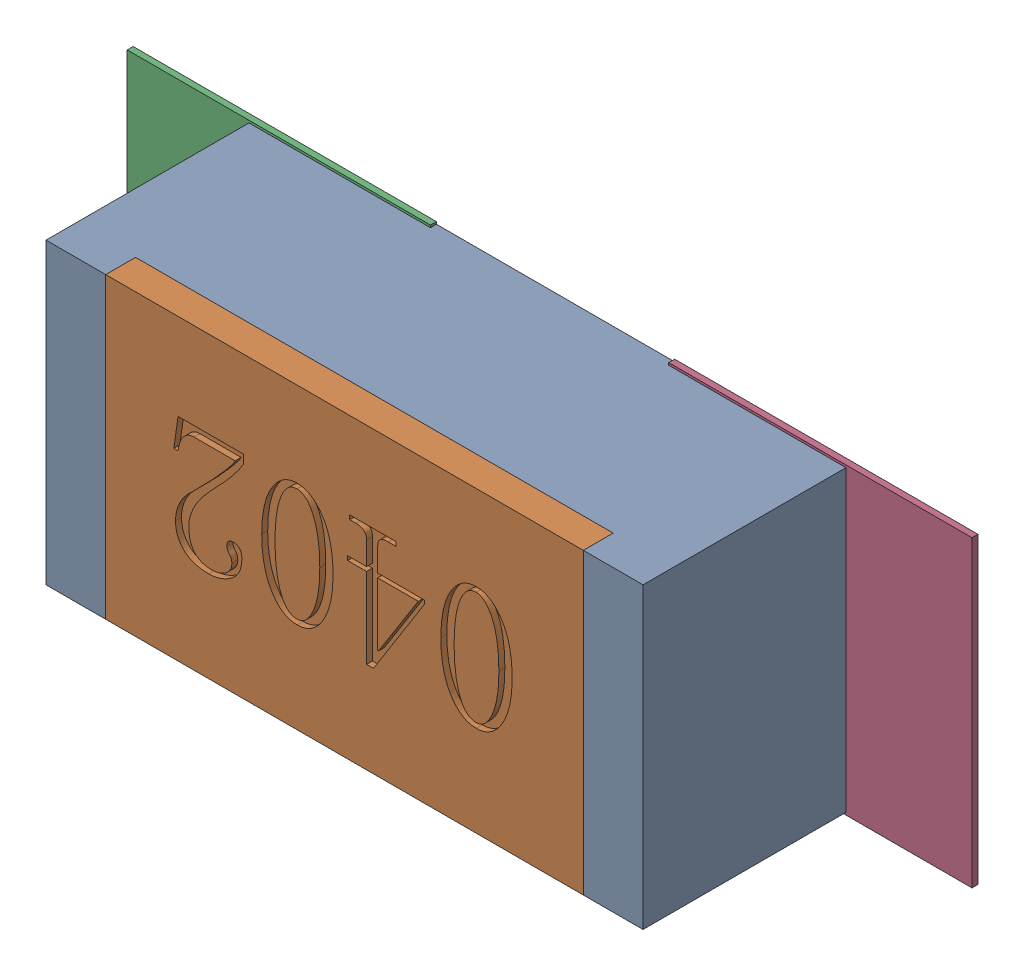
SolidWorks assembly R56, configuration Défaut. Lengths in mm.
Overall size (1.42 0.51 0.35).
5 component instances, 2 part files, 0 mates.
Components (placement in the parent):
- R0402-1: R0402 [Défaut] at (56.0324 -23.3425 0) x (-1 0 0) z (0 0 1) size (1 0.5 0.35)
- 6504207776-1: 6504207776 [Défaut] at (55.5824 -23.3427 0) size (0.51 0.51 0.01)
  - Extruded-1: Extruded [Défaut] at origin size (0.51 0.51 0.01)
- 6504207776-2: 6504207776 [Défaut] at (56.4895 -23.3427 0) size (0.51 0.51 0.01)
  - Extruded-1: Extruded [Défaut] at origin size (0.51 0.51 0.01)
